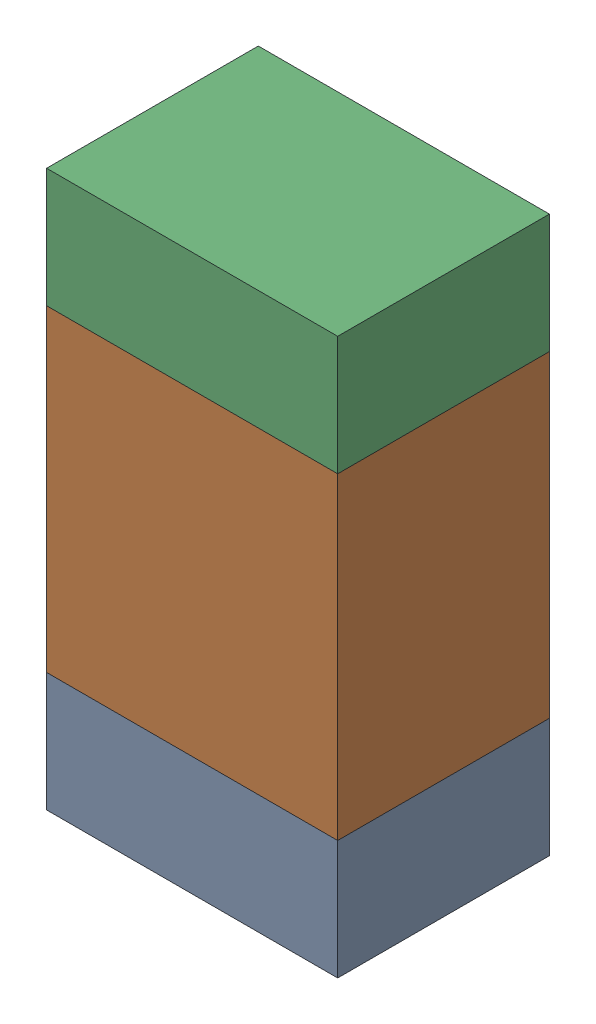
SolidWorks assembly R207PCB, configuration Default. Lengths in mm.
Overall size (0.55 1.05 0.4).
6 component instances, 2 part files, 0 mates.
Components (placement in the parent):
- 846483288-1: 846483288 [Default] at (91.8999 125.4876 0) size (0.55 0.22 0.4)
  - Extruded_12-1: Extruded_12 [Default] at origin size (0.55 0.22 0.4)
- 846483424-1: 846483424 [Default] at (91.8999 125.9001 0) size (0.55 0.6 0.4)
  - Extruded_13-1: Extruded_13 [Default] at origin size (0.55 0.6 0.4)
- 846483288-2: 846483288 [Default] at (91.8999 126.3126 0) size (0.55 0.22 0.4)
  - Extruded_12-1: Extruded_12 [Default] at origin size (0.55 0.22 0.4)
